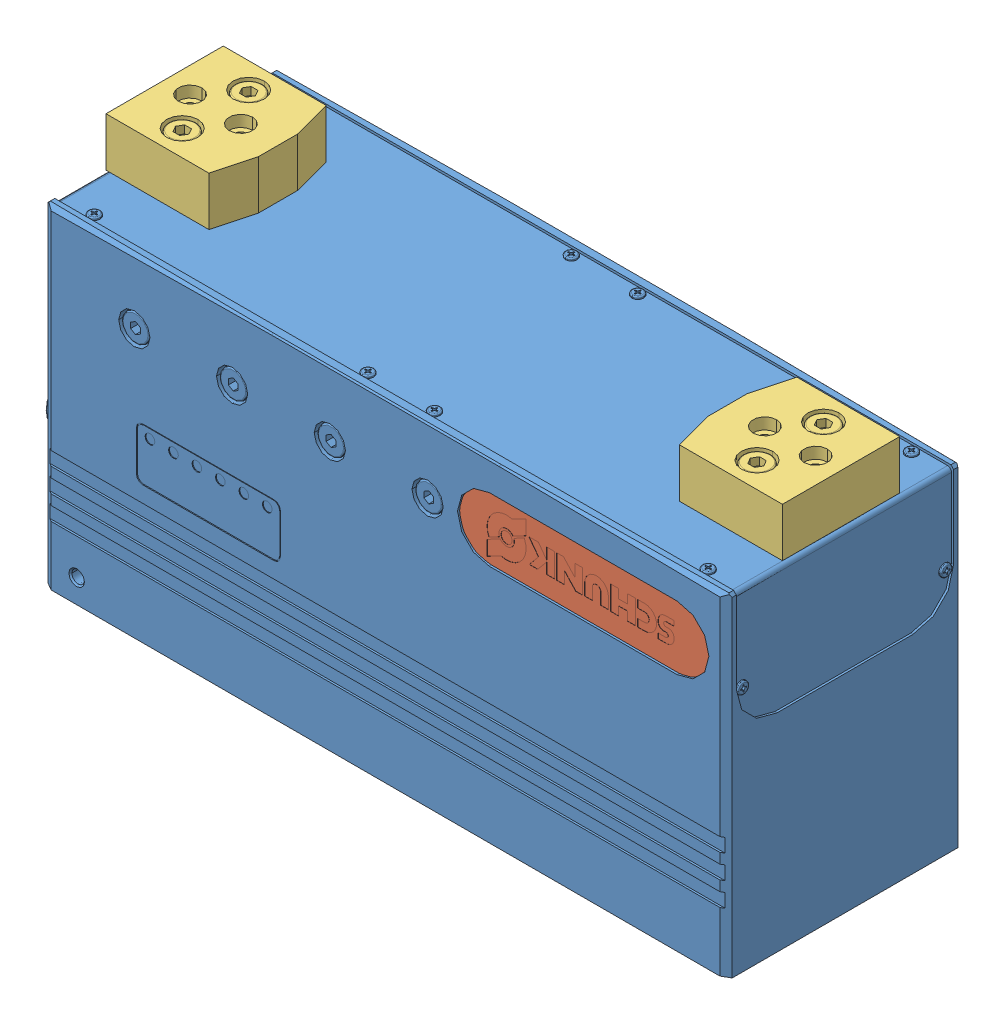
SolidWorks assembly SCHUNK_1328836_EGI_080_PN__0ohneohne, configuration Default. Lengths in mm.
Overall size (192.75 97.5 60).
4 component instances, 3 part files, 0 mates.
Components (placement in the parent):
- _SCHUNK_1013137_GEH_EGI_080_PN_2-1: _SCHUNK_1013137_GEH_EGI_080_PN_2 [Default] at origin size (192.75 85 60)
- _SCHUNK_9957615_Typenschild_16x64x0_3_4-1: _SCHUNK_9957615_Typenschild_16x64x0_3_4 [Default] at (50.55 69.45 29.3) x (-1 0 0) z (0 0 1) size (64 16 0.3)
- _SCHUNK_1013138_GBAEGI_080_6-1: _SCHUNK_1013138_GBAEGI_080_6 [Default] at (72 85 0) x (-1 0 0) z (0 0 -1) size (29 12.5 30)
- _SCHUNK_1013138_GBAEGI_080_6-2: _SCHUNK_1013138_GBAEGI_080_6 [Default] at (-72 85 0) size (29 12.5 30)
